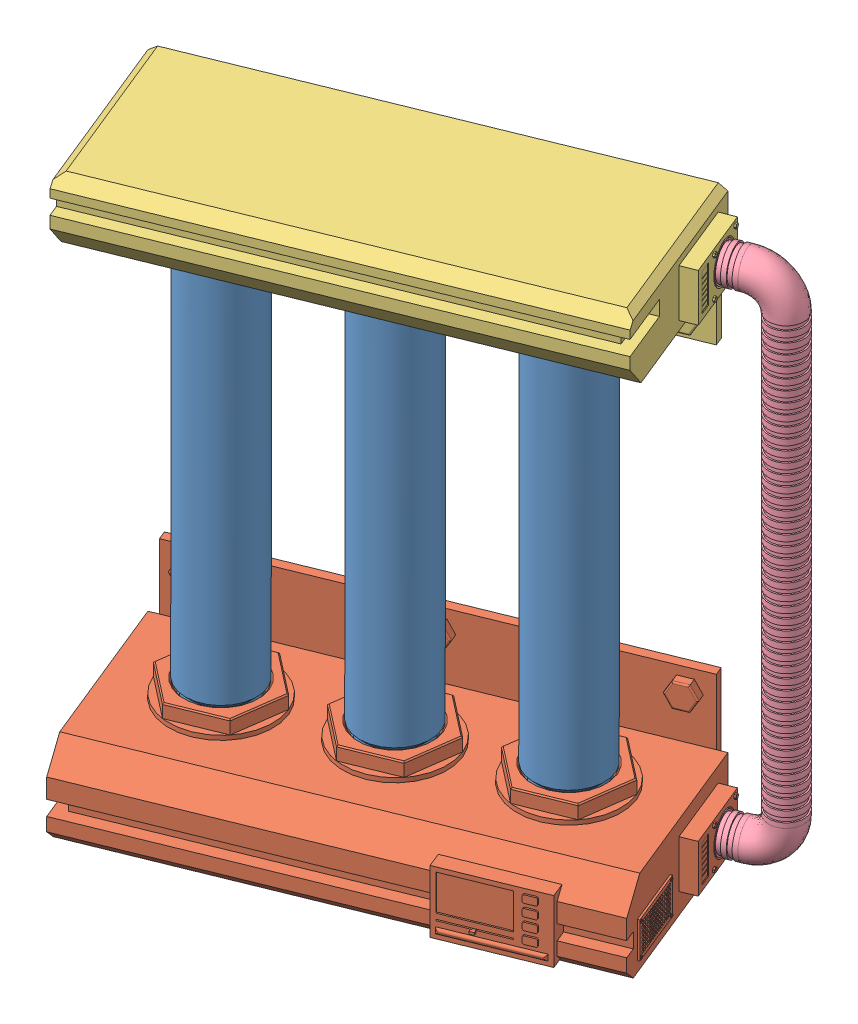
SolidWorks assembly SMT4 HA light, configuration Default. Lengths in mm.
Overall size (866.87 968 613.14).
6 component instances, 4 part files, 11 mates.
Components (placement in the parent):
- SMT4 v2 tube-1: SMT4 v2 tube [Default] at (151.0595 -125.2775 777.8796) size (120 753 120)
- SMT4 v2 base-1: SMT4 v2 base [Default] at (375.9766 -296.7775 733.7054) x (0.926429 0 -0.376469) z (0.376469 0 0.926429) size (782 250 344)
- SMT4 v2 tube-2: SMT4 v2 tube [Default] at (359.5061 -125.2775 693.1741) size (120 753 120)
- SMT4 v2 tube-3: SMT4 v2 tube [Default] at (567.9526 -125.2775 608.4686) size (120 753 120)
- SMT4 v2 top-1: SMT4 v2 top [Default] at (366.546 671.2225 710.4983) x (-0.926429 0 0.376469) z (0.376469 0 0.926429) size (778 237.5 315)
- SMT4 v2 pipe-4: SMT4 v2 pipe [Default] at (683.8395 -221.7775 495.2082) x (0.926429 0 -0.376469) z (0.376469 0 0.926429) size (135 893 60)
Mates (geometry in assembly coordinates):
- Tangent1: tangent: plane of SMT4 v2 tube-1 through (151.0595 -176.7775 777.8796) normal (0 -1 0); circle of SMT4 v2 base-1
- Concentric3: concentric anti-aligned: cylinder of SMT4 v2 tube-1 through (151.0595 -166.7775 777.8796) axis (0 -1 0) radius 60; cylinder of SMT4 v2 base-1 through (151.0595 -176.7775 777.8796) axis (0 1 0) radius 60
- Coincident4: coincident anti-aligned: plane of SMT4 v2 base-1 through (359.5061 -176.7775 693.1741) normal (0 1 0); plane of SMT4 v2 tube-2 through (359.5061 -176.7775 693.1741) normal (0 -1 0)
- Concentric4: concentric anti-aligned: cylinder of SMT4 v2 base-1 through (359.5061 -176.7775 693.1741) axis (0 1 0) radius 60; cylinder of SMT4 v2 tube-2 through (359.5061 -166.7775 693.1741) axis (0 -1 0) radius 60
- Coincident5: coincident anti-aligned: plane of SMT4 v2 base-1 through (567.9526 -176.7775 608.4686) normal (0 1 0); plane of SMT4 v2 tube-3 through (567.9526 -176.7775 608.4686) normal (0 -1 0)
- Concentric5: concentric anti-aligned: cylinder of SMT4 v2 base-1 through (567.9526 -176.7775 608.4686) axis (0 1 0) radius 60; cylinder of SMT4 v2 tube-3 through (567.9526 -166.7775 608.4686) axis (0 -1 0) radius 60
- Coincident6: coincident anti-aligned: plane of SMT4 v2 tube-3 through (567.9526 576.2225 608.4686) normal (0 1 0); plane of SMT4 v2 top-1 through (567.9526 576.2225 608.4686) normal (0 -1 0)
- Concentric6: concentric anti-aligned: cylinder of SMT4 v2 tube-3 through (567.9526 566.2225 608.4686) axis (0 1 0) radius 60; cylinder of SMT4 v2 top-1 through (567.9526 576.2225 608.4686) axis (0 -1 0) radius 60
- Concentric7: concentric anti-aligned: cylinder of SMT4 v2 tube-2 through (359.5061 566.2225 693.1741) axis (0 1 0) radius 60; cylinder of SMT4 v2 top-1 through (359.5061 576.2225 693.1741) axis (0 -1 0) radius 60
- Coincident9: coincident anti-aligned: plane of SMT4 v2 top-1 through (683.8395 611.2225 495.2082) normal (0.926429 0 -0.376469); plane of SMT4 v2 pipe-4 through (683.8395 611.2225 495.2082) normal (-0.926429 0 0.376469)
- Concentric10: concentric anti-aligned: cylinder of SMT4 v2 top-1 through (683.8395 611.2225 495.2082) axis (0.926429 0 -0.376469) radius 30; cylinder of SMT4 v2 pipe-4 through (734.7931 611.2225 474.5024) axis (-0.926429 0 0.376469) radius 30
